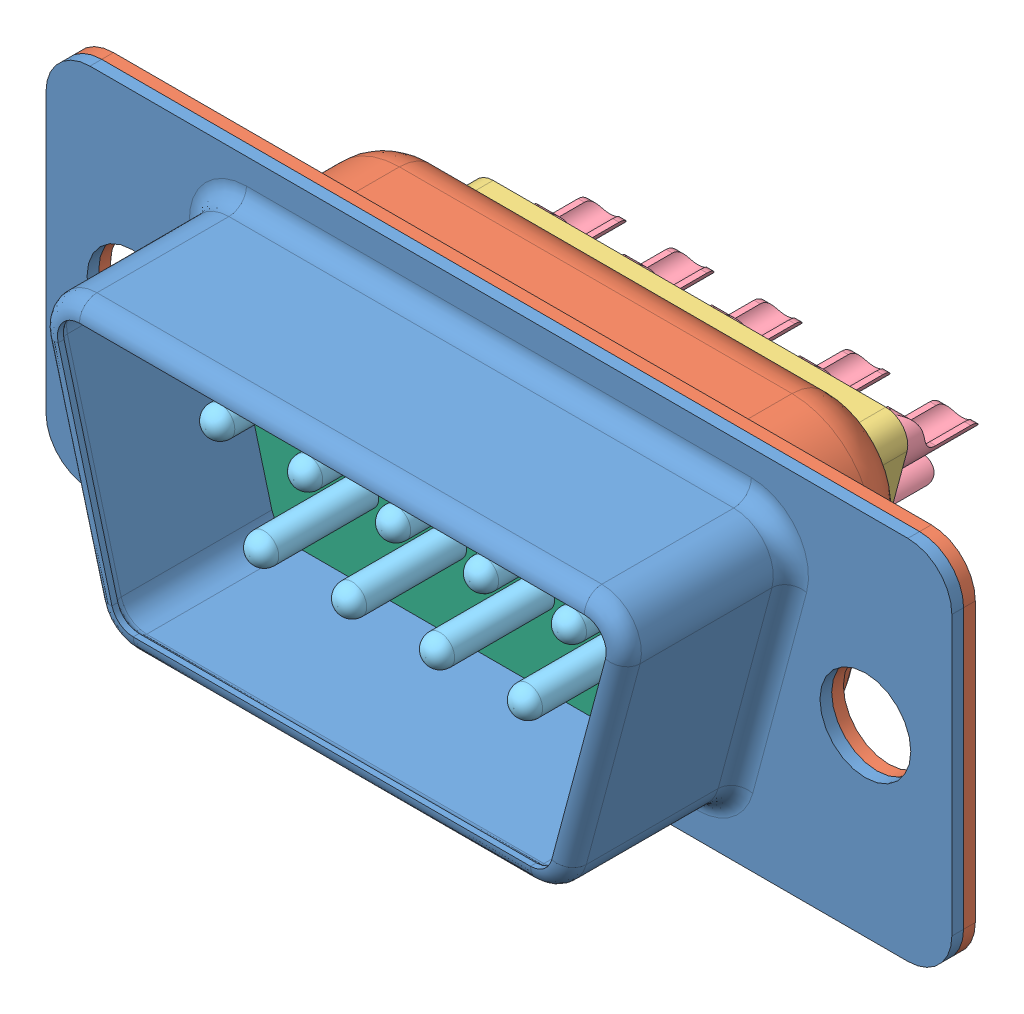
SolidWorks assembly A_DB9 - MALE, configuration Default. Lengths in mm.
Overall size (30.9 12.5 15.5).
22 component instances, 6 part files, 58 mates.
Components (placement in the parent):
- H_F_Fr - Male-1: H_F_Fr - Male [Default] at (9.0281 16.7349 21.5766) size (30.9 12.5 6.1)
- H_F_Ba-1: H_F_Ba [Default] at (9.0281 16.7349 21.5766) x (-1 0 0) z (0 0 -1) size (30.9 12.5 4.4)
- I_F_Fr-2: I_F_Fr [Default] at (9.0281 16.7349 15.4766) size (14.89 6.5 6.1)
- Connector-1: Connector [Default] at (15.0287 18.2349 17.1766) x (0 1 0) z (0 0 -1) size (1.47 1.47 5)
- Connector-2: Connector [Default] at (12.0287 18.2349 17.1766) x (0 1 0) z (0 0 -1) size (1.47 1.47 5)
- Connector-3: Connector [Default] at (9.0287 18.2349 17.1766) x (0 1 0) z (0 0 -1) size (1.47 1.47 5)
- Connector-4: Connector [Default] at (6.0287 18.2349 17.1766) x (0 1 0) z (0 0 -1) size (1.47 1.47 5)
- Connector-5: Connector [Default] at (3.0287 18.2349 17.1766) x (0 1 0) z (0 0 -1) size (1.47 1.47 5)
- Connector-7: Connector [Default] at (13.5287 15.2349 17.1766) x (0 -1 0) z (0 0 -1) size (1.47 1.47 5)
- Connector-8: Connector [Default] at (10.5287 15.2349 17.1766) x (0 -1 0) z (0 0 -1) size (1.47 1.47 5)
- Connector-9: Connector [Default] at (7.5287 15.2349 17.1766) x (0 -1 0) z (0 0 -1) size (1.47 1.47 5)
- Connector-10: Connector [Default] at (4.5287 15.2349 17.1766) x (0 -1 0) z (0 0 -1) size (1.47 1.47 5)
- Connector_MaleSLDPRT-1: Connector_MaleSLDPRT [Default] at (3.0287 18.2349 19.9766) size (1 1 6)
- Connector_MaleSLDPRT-2: Connector_MaleSLDPRT [Default] at (6.0287 18.2349 19.9766) x (0.987351 0.158553 0) z (0 0 1) size (1 1 6)
- Connector_MaleSLDPRT-3: Connector_MaleSLDPRT [Default] at (9.0287 18.2349 19.9766) x (0.959125 0.282984 0) z (0 0 1) size (1 1 6)
- Connector_MaleSLDPRT-4: Connector_MaleSLDPRT [Default] at (12.0287 18.2349 19.9766) x (0.928571 0.371154 0) z (0 0 1) size (1 1 6)
- Connector_MaleSLDPRT-5: Connector_MaleSLDPRT [Default] at (15.0287 18.2349 19.9766) x (0.906989 0.421154 0) z (0 0 1) size (1 1 6)
- Connector_MaleSLDPRT-6: Connector_MaleSLDPRT [Default] at (4.5287 15.2349 19.9766) x (0.902849 0.429957 0) z (0 0 1) size (1 1 6)
- Connector_MaleSLDPRT-7: Connector_MaleSLDPRT [Default] at (7.5287 15.2349 19.9766) x (0.919615 0.39282 0) z (0 0 1) size (1 1 6)
- Connector_MaleSLDPRT-8: Connector_MaleSLDPRT [Default] at (10.5287 15.2349 19.9766) x (0.952324 0.305088 0) z (0 0 1) size (1 1 6)
- Connector_MaleSLDPRT-9: Connector_MaleSLDPRT [Default] at (13.5287 15.2349 19.9766) x (0.985697 0.168526 0) z (0 0 1) size (1 1 6)
- H_F_Fr - Male - Copy-1: H_F_Fr - Male - Copy [Default] at (8.8327 16.5849 21.5766) size (19.32 8.95 0.5)
Mates (geometry in assembly coordinates):
- Coincident1: coincident: moEndPointRef_w of H_F_Fr - Male-1; plane of H_F_Fr - Male-1 through (9.0281 16.7349 27.6766) normal (0 0 1)
- Coincident2: coincident: plane of H_F_Fr - Male-1 through (15.3761 15.0339 21.9766) normal (-0.965926 0.258819 0); plane of H_F_Fr - Male-1 through (15.3761 15.0339 27.6766) normal (0.965926 -0.258819 0)
- Coincident3: coincident: plane of H_F_Fr - Male-1 through (9.0281 19.9849 21.9766) normal (0 -1 0); plane of H_F_Fr - Male-1 through (9.0281 19.9849 27.6766) normal (0 1 0)
- Coincident4: coincident: plane of H_F_Fr - Male-1 through (9.0281 16.7349 21.5766) normal (0 0 -1); plane of H_F_Ba-1 through (9.0281 16.7349 21.5766) normal (0 0 1)
- Coincident5: coincident: line of H_F_Fr - Male-1 through (-4.9219 22.9849 21.5766) axis (1 0 0); line of H_F_Ba-1 through (22.9781 22.9849 21.5766) axis (-1 0 0)
- Coincident6: coincident: line of H_F_Fr - Male-1 through (-6.4219 21.4849 21.5766) axis (0 -1 0); line of H_F_Ba-1 through (-6.4219 21.4849 21.5766) axis (0 -1 0)
- Coincident7: coincident: plane of H_F_Ba-1 through (2.3311 19.9849 17.1766) normal (0 -1 0); plane of I_F_Fr-2 through (9.0281 19.9849 21.5766) normal (0 1 0)
- Coincident10: coincident: plane of H_F_Ba-1 through (16.4497 19.0408 17.1766) normal (-0.965926 0.258819 0); plane of I_F_Fr-2 through (15.3761 15.0339 21.5766) normal (0.965926 -0.258819 0)
- Coincident11: coincident: plane of H_F_Fr - Male-1 through (9.0281 16.7349 21.5766) normal (0 0 -1); plane of I_F_Fr-2 through (9.0281 16.7349 21.5766) normal (0 0 1)
- Concentric1: concentric: cylinder of I_F_Fr-2 through (15.0287 18.2349 15.4756) axis (0 0 1) radius 0.7; cylinder of Connector-1 through (15.0287 18.2349 12.1766) axis (0 0 1) radius 0.7375
- Parallel1: parallel: plane of I_F_Fr-2 through (9.0281 19.9849 21.5766) normal (0 1 0); plane of Connector-1 through (17.0287 17.9974 12.5766) normal (0 1 0)
- Distance1: distance = 3.3 mm: plane of Connector-1 through (15.0287 18.2349 12.1766) normal (0 0 -1); plane of I_F_Fr-2 through (9.0281 16.7349 15.4766) normal (0 0 -1)
- Concentric2: concentric: cylinder of I_F_Fr-2 through (12.0287 18.2349 15.4756) axis (0 0 1) radius 0.7; cylinder of Connector-2 through (12.0287 18.2349 12.1766) axis (0 0 1) radius 0.7375
- Parallel2: parallel: plane of I_F_Fr-2 through (9.0281 19.9849 21.5766) normal (0 1 0); plane of Connector-2 through (14.0287 17.9974 12.5766) normal (0 1 0)
- Distance2: distance = 3.3 mm: plane of Connector-2 through (12.0287 18.2349 12.1766) normal (0 0 -1); plane of I_F_Fr-2 through (9.0281 16.7349 15.4766) normal (0 0 -1)
- Concentric3: concentric: cylinder of I_F_Fr-2 through (9.0287 18.2349 15.4756) axis (0 0 1) radius 0.7; cylinder of Connector-3 through (9.0287 18.2349 12.1766) axis (0 0 1) radius 0.7375
- Parallel3: parallel: plane of I_F_Fr-2 through (9.0281 19.9849 21.5766) normal (0 1 0); plane of Connector-3 through (11.0287 17.9974 12.5766) normal (0 1 0)
- Distance3: distance = 3.3 mm: plane of Connector-3 through (9.0287 18.2349 12.1766) normal (0 0 -1); plane of I_F_Fr-2 through (9.0281 16.7349 15.4766) normal (0 0 -1)
- Concentric4: concentric: cylinder of I_F_Fr-2 through (6.0287 18.2349 15.4756) axis (0 0 1) radius 0.7; cylinder of Connector-4 through (6.0287 18.2349 12.1766) axis (0 0 1) radius 0.7375
- Parallel4: parallel: plane of I_F_Fr-2 through (9.0281 19.9849 21.5766) normal (0 1 0); plane of Connector-4 through (8.0287 17.9974 12.5766) normal (0 1 0)
- Distance4: distance = 3.3 mm: plane of Connector-4 through (6.0287 18.2349 12.1766) normal (0 0 -1); plane of I_F_Fr-2 through (9.0281 16.7349 15.4766) normal (0 0 -1)
- Concentric5: concentric: cylinder of I_F_Fr-2 through (3.0287 18.2349 15.4756) axis (0 0 1) radius 0.7; cylinder of Connector-5 through (3.0287 18.2349 12.1766) axis (0 0 1) radius 0.7375
- Parallel5: parallel: plane of I_F_Fr-2 through (9.0281 19.9849 21.5766) normal (0 1 0); plane of Connector-5 through (5.0287 17.9974 12.5766) normal (0 1 0)
- Distance5: distance = 3.3 mm: plane of Connector-5 through (3.0287 18.2349 12.1766) normal (0 0 -1); plane of I_F_Fr-2 through (9.0281 16.7349 15.4766) normal (0 0 -1)
- Concentric7: concentric: cylinder of I_F_Fr-2 through (13.5287 15.2349 15.4756) axis (0 0 1) radius 0.7; cylinder of Connector-7 through (13.5287 15.2349 12.1766) axis (0 0 1) radius 0.7375
- Parallel6: parallel: plane of I_F_Fr-2 through (9.0281 13.4849 21.5766) normal (0 -1 0); plane of Connector-7 through (11.5287 15.4724 12.5766) normal (0 -1 0)
- Distance6: distance = 3.3 mm: plane of Connector-7 through (13.5287 15.2349 12.1766) normal (0 0 -1); plane of I_F_Fr-2 through (9.0281 16.7349 15.4766) normal (0 0 -1)
- Concentric8: concentric: cylinder of I_F_Fr-2 through (10.5287 15.2349 15.4756) axis (0 0 1) radius 0.7; cylinder of Connector-8 through (10.5287 15.2349 12.1766) axis (0 0 1) radius 0.7375
- Parallel7: parallel: plane of I_F_Fr-2 through (9.0281 13.4849 21.5766) normal (0 -1 0); plane of Connector-8 through (8.5287 15.4724 12.5766) normal (0 -1 0)
- Distance7: distance = 3.3 mm: plane of Connector-8 through (10.5287 15.2349 12.1766) normal (0 0 -1); plane of I_F_Fr-2 through (9.0281 16.7349 15.4766) normal (0 0 -1)
- Concentric9: concentric: cylinder of I_F_Fr-2 through (7.5287 15.2349 15.4756) axis (0 0 1) radius 0.7; cylinder of Connector-9 through (7.5287 15.2349 12.1766) axis (0 0 1) radius 0.7375
- Parallel8: parallel: plane of I_F_Fr-2 through (9.0281 13.4849 21.5766) normal (0 -1 0); plane of Connector-9 through (5.5287 15.4724 12.5766) normal (0 -1 0)
- Distance8: distance = 3.3 mm: plane of Connector-9 through (7.5287 15.2349 12.1766) normal (0 0 -1); plane of I_F_Fr-2 through (9.0281 16.7349 15.4766) normal (0 0 -1)
- Concentric10: concentric: cylinder of I_F_Fr-2 through (4.5287 15.2349 15.4756) axis (0 0 1) radius 0.7; cylinder of Connector-10 through (4.5287 15.2349 12.1766) axis (0 0 1) radius 0.7375
- Parallel9: parallel: plane of I_F_Fr-2 through (9.0281 13.4849 21.5766) normal (0 -1 0); plane of Connector-10 through (2.5287 15.4724 12.5766) normal (0 -1 0)
- Distance9: distance = 3.3 mm: plane of Connector-10 through (4.5287 15.2349 12.1766) normal (0 0 -1); plane of I_F_Fr-2 through (9.0281 16.7349 15.4766) normal (0 0 -1)
- Concentric11: concentric: cylinder of I_F_Fr-2 through (3.0287 18.2349 15.4756) axis (0 0 1) radius 0.7; cylinder of Connector_MaleSLDPRT-1 through (3.0287 18.2349 25.9766) axis (0 0 -1) radius 0.5
- Distance10: distance = 4.4 mm: plane of Connector_MaleSLDPRT-1 through (3.0287 18.2349 25.9766) normal (0 0 1); plane of I_F_Fr-2 through (9.0281 16.7349 21.5766) normal (0 0 1)
- Concentric12: concentric: cylinder of I_F_Fr-2 through (6.0287 18.2349 15.4756) axis (0 0 1) radius 0.7; cylinder of Connector_MaleSLDPRT-2 through (6.0287 18.2349 25.9766) axis (0 0 -1) radius 0.5
- Distance11: distance = 4.4 mm: plane of Connector_MaleSLDPRT-2 through (6.0287 18.2349 25.9766) normal (0 0 1); plane of I_F_Fr-2 through (9.0281 16.7349 21.5766) normal (0 0 1)
- Concentric13: concentric: cylinder of I_F_Fr-2 through (9.0287 18.2349 15.4756) axis (0 0 1) radius 0.7; cylinder of Connector_MaleSLDPRT-3 through (9.0287 18.2349 25.9766) axis (0 0 -1) radius 0.5
- Distance12: distance = 4.4 mm: plane of Connector_MaleSLDPRT-3 through (9.0287 18.2349 25.9766) normal (0 0 1); plane of I_F_Fr-2 through (9.0281 16.7349 21.5766) normal (0 0 1)
- Concentric14: concentric: cylinder of I_F_Fr-2 through (12.0287 18.2349 15.4756) axis (0 0 1) radius 0.7; cylinder of Connector_MaleSLDPRT-4 through (12.0287 18.2349 25.9766) axis (0 0 -1) radius 0.5
- Distance13: distance = 4.4 mm: plane of Connector_MaleSLDPRT-4 through (12.0287 18.2349 25.9766) normal (0 0 1); plane of I_F_Fr-2 through (9.0281 16.7349 21.5766) normal (0 0 1)
- Concentric15: concentric: cylinder of I_F_Fr-2 through (15.0287 18.2349 15.4756) axis (0 0 1) radius 0.7; cylinder of Connector_MaleSLDPRT-5 through (15.0287 18.2349 25.9766) axis (0 0 -1) radius 0.5
- Distance14: distance = 4.4 mm: plane of Connector_MaleSLDPRT-5 through (15.0287 18.2349 25.9766) normal (0 0 1); plane of I_F_Fr-2 through (9.0281 16.7349 21.5766) normal (0 0 1)
- Concentric16: concentric: cylinder of I_F_Fr-2 through (4.5287 15.2349 15.4756) axis (0 0 1) radius 0.7; cylinder of Connector_MaleSLDPRT-6 through (4.5287 15.2349 25.9766) axis (0 0 -1) radius 0.5
- Distance15: distance = 4.4 mm: plane of Connector_MaleSLDPRT-6 through (4.5287 15.2349 25.9766) normal (0 0 1); plane of I_F_Fr-2 through (9.0281 16.7349 21.5766) normal (0 0 1)
- Concentric17: concentric: cylinder of I_F_Fr-2 through (7.5287 15.2349 15.4756) axis (0 0 1) radius 0.7; cylinder of Connector_MaleSLDPRT-7 through (7.5287 15.2349 25.9766) axis (0 0 -1) radius 0.5
- Distance16: distance = 4.4 mm: plane of Connector_MaleSLDPRT-7 through (7.5287 15.2349 25.9766) normal (0 0 1); plane of I_F_Fr-2 through (9.0281 16.7349 21.5766) normal (0 0 1)
- Concentric18: concentric: cylinder of I_F_Fr-2 through (10.5287 15.2349 15.4756) axis (0 0 1) radius 0.7; cylinder of Connector_MaleSLDPRT-8 through (10.5287 15.2349 25.9766) axis (0 0 -1) radius 0.5
- Distance17: distance = 4.4 mm: plane of Connector_MaleSLDPRT-8 through (10.5287 15.2349 25.9766) normal (0 0 1); plane of I_F_Fr-2 through (9.0281 16.7349 21.5766) normal (0 0 1)
- Concentric19: concentric: cylinder of I_F_Fr-2 through (13.5287 15.2349 15.4756) axis (0 0 1) radius 0.7; cylinder of Connector_MaleSLDPRT-9 through (13.5287 15.2349 25.9766) axis (0 0 -1) radius 0.5
- Distance18: distance = 4.4 mm: plane of Connector_MaleSLDPRT-9 through (13.5287 15.2349 25.9766) normal (0 0 1); plane of I_F_Fr-2 through (9.0281 16.7349 21.5766) normal (0 0 1)
- Coincident12: coincident: plane of H_F_Ba-1 through (9.0281 16.7349 21.5766) normal (0 0 1); plane of H_F_Fr - Male - Copy-1 through (0.2217 20.0099 21.5766) normal (0 0 -1)
- Coincident13: coincident: plane of H_F_Fr - Male-1 through (0.4171 21.0599 27.4766) normal (0 -1 0); plane of H_F_Fr - Male - Copy-1 through (0.2217 21.0599 22.0766) normal (0 1 0)
- Coincident14: coincident: plane of H_F_Fr - Male-1 through (18.5085 19.9269 27.4766) normal (-0.965926 0.258819 0); plane of H_F_Fr - Male - Copy-1 through (18.4579 19.7381 22.0766) normal (0.965926 -0.258819 0)
- Parallel10: parallel: plane of H_F_Ba-1 through (15.7252 19.2349 17.1766) normal (0 0 -1); plane of I_F_Fr-2 through (9.0281 16.7349 15.4766) normal (0 0 -1)
